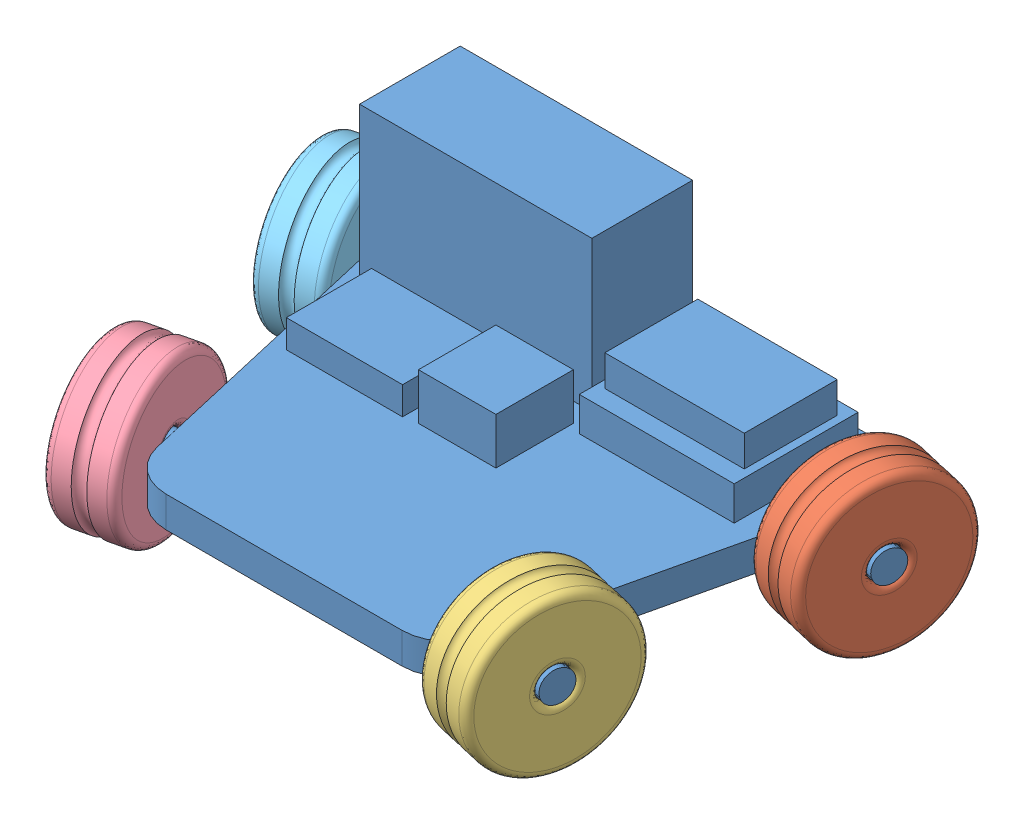
SolidWorks assembly Assem1, configuration Default. Lengths in mm.
Overall size (402.06 174.25 297.32).
5 component instances, 5 part files, 8 mates.
Components (placement in the parent):
- car body-1: car body [Default] at (105.536 158.9023 296.4882) size (380.18 117 260)
- car wheels-1: car wheels [Default] at (273.889 148.9558 234.4388) x (0.102599 0.889836 -0.444596) z (0.974391 0 0.22486) size (100 100 40)
- car wheels - Copy-1: car wheels - Copy [Default] at (233.7297 148.9558 408.4626) x (0.22486 0 -0.974391) z (0.974391 0 0.22486) size (100 100 40)
- car wheels - Copy (2)-1: car wheels - Copy (2) [Default] at (-22.6576 148.9558 408.4626) x (0.22486 0 0.974391) z (-0.974391 0 0.22486) size (100 100 40)
- car wheels - Copy (3)-1: car wheels - Copy (3) [Default] at (-62.8169 148.9558 234.4388) x (0.22486 0 0.974391) z (-0.974391 0 0.22486) size (100 100 40)
Mates (geometry in assembly coordinates):
- Concentric1: concentric: cylinder of car body-1 through (293.3768 148.9558 238.936) axis (-0.974391 0 -0.22486) radius 10; cylinder of car wheels-1 through (254.4012 148.9558 229.9416) axis (0.974391 0 0.22486) radius 10
- Coincident1: coincident aligned: plane of car body-1 through (293.3768 148.9558 238.936) normal (0.974391 0 0.22486); plane of car wheels-1 through (293.3768 148.9558 238.936) normal (0.974391 0 0.22486)
- Concentric2: concentric: cylinder of car body-1 through (253.2175 148.9558 412.9598) axis (-0.974391 0 -0.22486) radius 10; cylinder of car wheels - Copy-1 through (214.2418 148.9558 403.9655) axis (0.974391 0 0.22486) radius 10
- Coincident2: coincident aligned: plane of car body-1 through (253.2175 148.9558 412.9598) normal (0.974391 0 0.22486); circle of car wheels - Copy-1
- Concentric3: concentric: cylinder of car body-1 through (-42.1454 148.9558 412.9598) axis (0.974391 0 -0.22486) radius 10; cylinder of car wheels - Copy (2)-1 through (-3.1698 148.9558 403.9655) axis (-0.974391 0 0.22486) radius 10
- Coincident3: coincident aligned: plane of car body-1 through (-42.1454 148.9558 412.9598) normal (-0.974391 0 0.22486); plane of car wheels - Copy (2)-1 through (-42.1454 148.9558 412.9598) normal (-0.974391 0 0.22486)
- Concentric4: concentric: cylinder of car body-1 through (-82.3048 148.9558 238.936) axis (0.974391 0 -0.22486) radius 10; cylinder of car wheels - Copy (3)-1 through (-43.3291 148.9558 229.9416) axis (-0.974391 0 0.22486) radius 10
- Coincident4: coincident aligned: plane of car body-1 through (-82.3048 148.9558 238.936) normal (-0.974391 0 0.22486); plane of car wheels - Copy (3)-1 through (-82.3048 148.9558 238.936) normal (-0.974391 0 0.22486)
